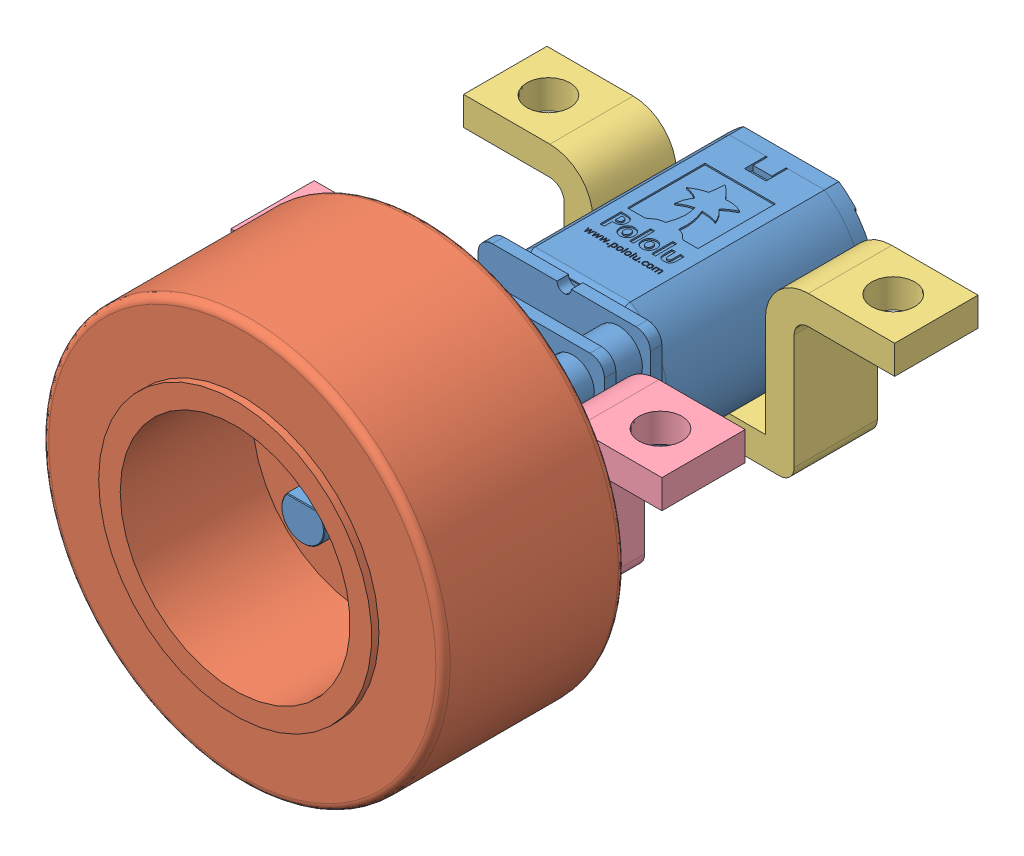
SolidWorks assembly Drive Unit Assy, configuration Default. Lengths in mm.
Overall size (30 27.94 40.5).
4 component instances, 4 part files, 8 mates.
Components (placement in the parent):
- Micro Metal Gearmotor HP 6V-1: Micro Metal Gearmotor HP 6V [Default] at origin size (12 10.04 35.8)
- Wheel-1: Wheel [Default] at (0 0 10.5) size (27.94 27.94 13.7)
- Inner Motor Bracket-1: Inner Motor Bracket [Default] at (0 0 -10.1) size (30 12 5.8)
- Outer Motor Bracket-1: Outer Motor Bracket [Default] at (0 0 6.1) size (30 12 5.8)
Mates (geometry in assembly coordinates):
- Concentric1: concentric anti-aligned: cylinder of Micro Metal Gearmotor HP 6V-1 through (0 0 13.525) axis (0 0 1) radius 1.5; cylinder of Wheel-1 through (0 0 10.5) axis (0 0 -1) radius 1.5
- Coincident1: coincident anti-aligned: plane of Micro Metal Gearmotor HP 6V-1 through (0 0 10) normal (0 0 1); plane of Wheel-1 through (0 9.5 10) normal (0 0 -1)
- Coincident2: coincident aligned: plane of Micro Metal Gearmotor HP 6V-1 through (-6 5 9) normal (0 0 1); plane of Outer Motor Bracket-1 through (-9 2 9) normal (0 0 1)
- Width1: width aligned: plane of Outer Motor Bracket-1 through (-6 -5 9) normal (1 0 0); plane of Micro Metal Gearmotor HP 6V-1 through (6 -5 9) normal (-1 0 0); plane of Outer Motor Bracket-1 through (6 5 9) normal (1 0 0); plane of Micro Metal Gearmotor HP 6V-1 through (-6 5 3.2) normal (-1 0 0)
- Coincident3: coincident anti-aligned: plane of Micro Metal Gearmotor HP 6V-1 through (6 -5 9) normal (0 -1 0); plane of Outer Motor Bracket-1 through (-6 -5 9) normal (0 1 0)
- Width2: width anti-aligned: plane of Inner Motor Bracket-1 through (15 5 -7.2) normal (1 0 0); plane of Outer Motor Bracket-1 through (-15 3 -7.2) normal (-1 0 0); plane of Inner Motor Bracket-1 through (-15 3 9) normal (-1 0 0); plane of Outer Motor Bracket-1 through (15 5 9) normal (1 0 0)
- Coincident4: coincident aligned: plane of Inner Motor Bracket-1 through (-15 5 -7.2) normal (0 1 0); plane of Outer Motor Bracket-1 through (-15 5 9) normal (0 1 0)
- Distance1: distance = 22 mm anti-aligned: plane of Inner Motor Bracket-1 through (-9 2 -13) normal (0 0 -1); plane of Outer Motor Bracket-1 through (-9 2 9) normal (0 0 1)
